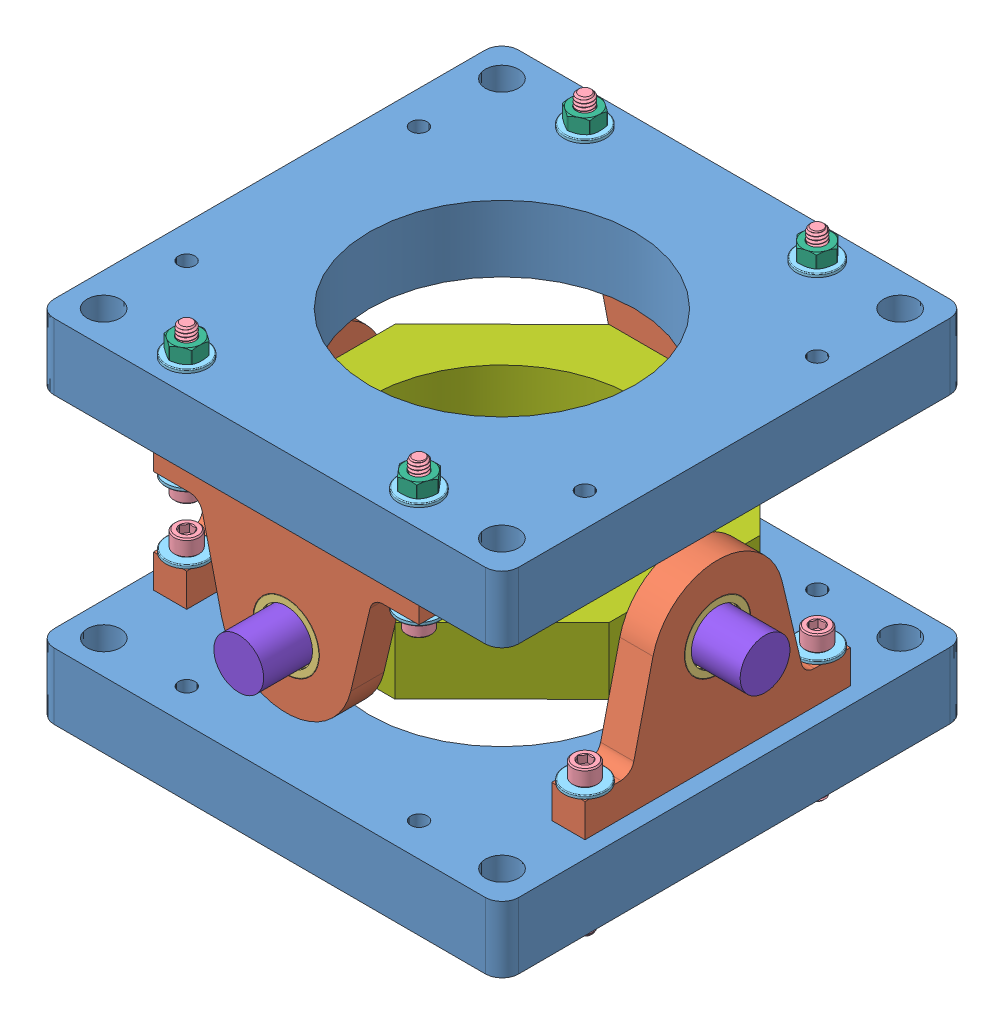
SolidWorks assembly Test Assembly Fixed, configuration Default. Lengths in mm.
Overall size (201.43 158.78 201.4).
62 component instances, 8 part files, 6 mates.
Components (placement in the parent):
- Intermediate Ring with Brackets-1: Intermediate Ring with Brackets [Default] at (212.401 138.376 28.4438) size (177.8 104.64 177.8)
  - Intermediate Ring-2: Intermediate Ring [Default] at (-88.8543 79.5311 225.6413) size (177.8 25.4 177.8)
  - Crosstree Bracket Assembly-1: Crosstree Bracket Assembly [Default] at (-114.4432 107.4664 379.2209) x (1 0 0) z (0 0 -1) size (104.78 104.64 15.88)
    - Crosstree Bracket-1: Crosstree Bracket [Default] at (25.5889 69.8453 71.0296) size (101.6 67.31 12.7)
    - 5905K26_Needle-Roller Bearing-1: 5905K26_Needle-Roller Bearing [5905K26] at (25.5889 69.8453 77.3796) x (-0.328056 0.944658 0) z (0 0 1) size (25.4 25.4 12.7)
    - 90128A253_Zinc-Plated Alloy Steel Socket Head Screw-1: 90128A253_Zinc-Plated Alloy Steel Socket Head Screw [90128A253] at (-18.8611 19.6803 77.3796) x (-0.333308 0 0.942818) z (0 1 0) size (9.53 9.53 57.93)
    - 90107A029_316 Stainless Steel Washer-2: 90107A029_316 Stainless Steel Washer [90107A029] at (-18.8611 41.2703 77.3796) x (1 0 0) z (0 1 0) size (15.88 15.88 1.27)
    - 90128A253_Zinc-Plated Alloy Steel Socket Head Screw-2: 90128A253_Zinc-Plated Alloy Steel Socket Head Screw [90128A253] at (70.0389 19.6803 77.3796) x (1 0 0) z (0 1 0) size (9.53 9.53 57.93)
    - 90107A029_316 Stainless Steel Washer-3: 90107A029_316 Stainless Steel Washer [90107A029] at (70.0389 41.2703 77.3796) x (1 0 0) z (0 1 0) size (15.88 15.88 1.27)
  - Crosstree Bracket Assembly-2: Crosstree Bracket Assembly [Default] at (-114.4432 107.4664 226.8209) x (1 0 0) z (0 0 -1) size (104.78 104.64 15.88)
    - Crosstree Bracket-1: Crosstree Bracket [Default] at (25.5889 69.8453 71.0296) size (101.6 67.31 12.7)
    - 5905K26_Needle-Roller Bearing-1: 5905K26_Needle-Roller Bearing [5905K26] at (25.5889 69.8453 77.3796) x (-0.328056 0.944658 0) z (0 0 1) size (25.4 25.4 12.7)
    - 90128A253_Zinc-Plated Alloy Steel Socket Head Screw-1: 90128A253_Zinc-Plated Alloy Steel Socket Head Screw [90128A253] at (-18.8611 19.6803 77.3796) x (-0.333308 0 0.942818) z (0 1 0) size (9.53 9.53 57.93)
    - 90107A029_316 Stainless Steel Washer-2: 90107A029_316 Stainless Steel Washer [90107A029] at (-18.8611 41.2703 77.3796) x (1 0 0) z (0 1 0) size (15.88 15.88 1.27)
    - 90128A253_Zinc-Plated Alloy Steel Socket Head Screw-2: 90128A253_Zinc-Plated Alloy Steel Socket Head Screw [90128A253] at (70.0389 19.6803 77.3796) x (1 0 0) z (0 1 0) size (9.53 9.53 57.93)
    - 90107A029_316 Stainless Steel Washer-3: 90107A029_316 Stainless Steel Washer [90107A029] at (70.0389 41.2703 77.3796) x (1 0 0) z (0 1 0) size (15.88 15.88 1.27)
  - 1_4_20_Nut Washer Assembly-1: 1_4_20_Nut Washer Assembly [Default] at (-68.2154 77.2758 126.5121) x (0.004746 0 -0.999989) z (0 1 0) size (15.88 15.88 7.21)
    - 90107A029_316 Stainless Steel Washer-1: 90107A029_316 Stainless Steel Washer [90107A029] at (-22.8159 -23.9196 28.2903) size (15.88 15.88 1.27)
    - 95462A029_Medium-Strength Steel Hex Nut-1: 95462A029_Medium-Strength Steel Hex Nut [95462A029] at (-22.8159 -23.9196 31.7034) x (0.972065 0.23471 0) z (0 0 1) size (11.11 12.75 6.32)
  - 1_4_20_Nut Washer Assembly-2: 1_4_20_Nut Washer Assembly [Default] at (-104.6077 77.2758 165.8492) x (0.240016 0 0.970769) z (0 1 0) size (15.88 15.88 7.21)
    - 90107A029_316 Stainless Steel Washer-1: 90107A029_316 Stainless Steel Washer [90107A029] at (-22.8159 -23.9196 28.2903) size (15.88 15.88 1.27)
    - 95462A029_Medium-Strength Steel Hex Nut-1: 95462A029_Medium-Strength Steel Hex Nut [95462A029] at (-22.8159 -23.9196 31.7034) x (0.972065 0.23471 0) z (0 0 1) size (11.11 12.75 6.32)
  - 1_4_20_Nut Washer Assembly-3: 1_4_20_Nut Washer Assembly [Default] at (-104.6027 77.2758 318.2405) x (0.240311 0 0.970696) z (0 1 0) size (15.88 15.88 7.21)
    - 90107A029_316 Stainless Steel Washer-1: 90107A029_316 Stainless Steel Washer [90107A029] at (-22.8159 -23.9196 28.2903) size (15.88 15.88 1.27)
    - 95462A029_Medium-Strength Steel Hex Nut-1: 95462A029_Medium-Strength Steel Hex Nut [95462A029] at (-22.8159 -23.9196 31.7034) x (0.972065 0.23471 0) z (0 0 1) size (11.11 12.75 6.32)
  - 1_4_20_Nut Washer Assembly-4: 1_4_20_Nut Washer Assembly [Default] at (-34.5945 77.2758 270.2742) x (0.895836 0 -0.444384) z (0 1 0) size (15.88 15.88 7.21)
    - 90107A029_316 Stainless Steel Washer-1: 90107A029_316 Stainless Steel Washer [90107A029] at (-22.8159 -23.9196 28.2903) size (15.88 15.88 1.27)
    - 95462A029_Medium-Strength Steel Hex Nut-1: 95462A029_Medium-Strength Steel Hex Nut [95462A029] at (-22.8159 -23.9196 31.7034) x (0.972065 0.23471 0) z (0 0 1) size (11.11 12.75 6.32)
- Intermediate Ring with Brackets-2: Intermediate Ring with Brackets [Default] at (-102.0555 213.6515 343.0246) x (-0.000002 -0.002271 0.999997) z (0.999999 -0.001042 0) size (177.8 104.64 177.8)
  - Intermediate Ring-2: Intermediate Ring [Default] at (-88.8543 79.5311 225.6413) size (177.8 25.4 177.8)
  - Crosstree Bracket Assembly-1: Crosstree Bracket Assembly [Default] at (-114.4432 107.4664 379.2209) x (1 0 0) z (0 0 -1) size (104.78 104.64 15.88)
    - Crosstree Bracket-1: Crosstree Bracket [Default] at (25.5889 69.8453 71.0296) size (101.6 67.31 12.7)
    - 5905K26_Needle-Roller Bearing-1: 5905K26_Needle-Roller Bearing [5905K26] at (25.5889 69.8453 77.3796) x (-0.328056 0.944658 0) z (0 0 1) size (25.4 25.4 12.7)
    - 90128A253_Zinc-Plated Alloy Steel Socket Head Screw-1: 90128A253_Zinc-Plated Alloy Steel Socket Head Screw [90128A253] at (-18.8611 19.6803 77.3796) x (-0.333308 0 0.942818) z (0 1 0) size (9.53 9.53 57.93)
    - 90107A029_316 Stainless Steel Washer-2: 90107A029_316 Stainless Steel Washer [90107A029] at (-18.8611 41.2703 77.3796) x (1 0 0) z (0 1 0) size (15.88 15.88 1.27)
    - 90128A253_Zinc-Plated Alloy Steel Socket Head Screw-2: 90128A253_Zinc-Plated Alloy Steel Socket Head Screw [90128A253] at (70.0389 19.6803 77.3796) x (1 0 0) z (0 1 0) size (9.53 9.53 57.93)
    - 90107A029_316 Stainless Steel Washer-3: 90107A029_316 Stainless Steel Washer [90107A029] at (70.0389 41.2703 77.3796) x (1 0 0) z (0 1 0) size (15.88 15.88 1.27)
  - Crosstree Bracket Assembly-2: Crosstree Bracket Assembly [Default] at (-114.4432 107.4664 226.8209) x (1 0 0) z (0 0 -1) size (104.78 104.64 15.88)
    - Crosstree Bracket-1: Crosstree Bracket [Default] at (25.5889 69.8453 71.0296) size (101.6 67.31 12.7)
    - 5905K26_Needle-Roller Bearing-1: 5905K26_Needle-Roller Bearing [5905K26] at (25.5889 69.8453 77.3796) x (-0.328056 0.944658 0) z (0 0 1) size (25.4 25.4 12.7)
    - 90128A253_Zinc-Plated Alloy Steel Socket Head Screw-1: 90128A253_Zinc-Plated Alloy Steel Socket Head Screw [90128A253] at (-18.8611 19.6803 77.3796) x (-0.333308 0 0.942818) z (0 1 0) size (9.53 9.53 57.93)
    - 90107A029_316 Stainless Steel Washer-2: 90107A029_316 Stainless Steel Washer [90107A029] at (-18.8611 41.2703 77.3796) x (1 0 0) z (0 1 0) size (15.88 15.88 1.27)
    - 90128A253_Zinc-Plated Alloy Steel Socket Head Screw-2: 90128A253_Zinc-Plated Alloy Steel Socket Head Screw [90128A253] at (70.0389 19.6803 77.3796) x (1 0 0) z (0 1 0) size (9.53 9.53 57.93)
    - 90107A029_316 Stainless Steel Washer-3: 90107A029_316 Stainless Steel Washer [90107A029] at (70.0389 41.2703 77.3796) x (1 0 0) z (0 1 0) size (15.88 15.88 1.27)
  - 1_4_20_Nut Washer Assembly-1: 1_4_20_Nut Washer Assembly [Default] at (-68.2154 77.2758 126.5121) x (0.004746 0 -0.999989) z (0 1 0) size (15.88 15.88 7.21)
    - 90107A029_316 Stainless Steel Washer-1: 90107A029_316 Stainless Steel Washer [90107A029] at (-22.8159 -23.9196 28.2903) size (15.88 15.88 1.27)
    - 95462A029_Medium-Strength Steel Hex Nut-1: 95462A029_Medium-Strength Steel Hex Nut [95462A029] at (-22.8159 -23.9196 31.7034) x (0.972065 0.23471 0) z (0 0 1) size (11.11 12.75 6.32)
  - 1_4_20_Nut Washer Assembly-2: 1_4_20_Nut Washer Assembly [Default] at (-104.6077 77.2758 165.8492) x (0.240016 0 0.970769) z (0 1 0) size (15.88 15.88 7.21)
    - 90107A029_316 Stainless Steel Washer-1: 90107A029_316 Stainless Steel Washer [90107A029] at (-22.8159 -23.9196 28.2903) size (15.88 15.88 1.27)
    - 95462A029_Medium-Strength Steel Hex Nut-1: 95462A029_Medium-Strength Steel Hex Nut [95462A029] at (-22.8159 -23.9196 31.7034) x (0.972065 0.23471 0) z (0 0 1) size (11.11 12.75 6.32)
  - 1_4_20_Nut Washer Assembly-3: 1_4_20_Nut Washer Assembly [Default] at (-104.6027 77.2758 318.2405) x (0.240311 0 0.970696) z (0 1 0) size (15.88 15.88 7.21)
    - 90107A029_316 Stainless Steel Washer-1: 90107A029_316 Stainless Steel Washer [90107A029] at (-22.8159 -23.9196 28.2903) size (15.88 15.88 1.27)
    - 95462A029_Medium-Strength Steel Hex Nut-1: 95462A029_Medium-Strength Steel Hex Nut [95462A029] at (-22.8159 -23.9196 31.7034) x (0.972065 0.23471 0) z (0 0 1) size (11.11 12.75 6.32)
  - 1_4_20_Nut Washer Assembly-4: 1_4_20_Nut Washer Assembly [Default] at (-34.5945 77.2758 270.2742) x (0.895836 0 -0.444384) z (0 1 0) size (15.88 15.88 7.21)
    - 90107A029_316 Stainless Steel Washer-1: 90107A029_316 Stainless Steel Washer [90107A029] at (-22.8159 -23.9196 28.2903) size (15.88 15.88 1.27)
    - 95462A029_Medium-Strength Steel Hex Nut-1: 95462A029_Medium-Strength Steel Hex Nut [95462A029] at (-22.8159 -23.9196 31.7034) x (0.972065 0.23471 0) z (0 0 1) size (11.11 12.75 6.32)
- Crosstree Assembly-1: Crosstree Assembly [Default] at (80.4212 101.4137 143.2242) x (0.999999 -0.001042 0) z (0 0 1) size (201.4 26.18 201.4)
  - Crosstree-1: Crosstree [Default] at (43.0477 61.9283 110.8608) size (139.7 25.4 139.7)
  - Crosstree Bearing Rod-1: Crosstree Bearing Rod [Default] at (43.0477 74.6283 10.1618) x (-0.520451 0.853891 0) z (0.853891 0.520451 0) size (19.05 50.8 19.05)
  - Crosstree Bearing Rod-2: Crosstree Bearing Rod [Default] at (143.7467 74.6283 110.8608) x (0 0.853891 -0.520451) z (0 0.520451 0.853891) size (19.05 50.8 19.05)
  - Crosstree Bearing Rod-3: Crosstree Bearing Rod [Default] at (43.0477 74.6283 211.5599) x (0.520451 0.853891 0) z (-0.853891 0.520451 0) size (19.05 50.8 19.05)
  - Crosstree Bearing Rod-4: Crosstree Bearing Rod [Default] at (-57.6514 74.6283 110.8608) x (0 0.853891 0.520451) z (0 0.520451 -0.853891) size (19.05 50.8 19.05)
Mates (geometry in assembly coordinates):
- Concentric2: concentric anti-aligned: cylinder of Intermediate Ring with Brackets-1/Crosstree Bracket Assembly-1/5905K26_Needle-Roller Bearing-1 through (123.5466 175.9971 323.935) axis (0 0 -1) radius 11.6417; cylinder of Crosstree Assembly-1/Crosstree Bearing Rod-3 through (123.5466 175.9971 303.9841) axis (0 0 1) radius 9.525
- Concentric3: concentric aligned: cylinder of Intermediate Ring with Brackets-1/Crosstree Bracket Assembly-2/5905K26_Needle-Roller Bearing-1 through (123.5466 175.9971 171.535) axis (0 0 -1) radius 11.6417; cylinder of Crosstree Assembly-1/Crosstree Bearing Rod-1 through (123.5466 175.9971 204.186) axis (0 0 -1) radius 9.525
- Coincident1: coincident anti-aligned: plane of Intermediate Ring with Brackets-1/Crosstree Bracket Assembly-2/Crosstree Bracket-1 through (123.5466 175.9971 184.235) normal (0 0 1); plane of Crosstree Assembly-1/Crosstree-1 through (152.4927 188.667 184.235) normal (0 0 -1)
- Concentric4: concentric anti-aligned: cylinder of Intermediate Ring with Brackets-2/Crosstree Bracket Assembly-1/5905K26_Needle-Roller Bearing-1 through (193.3966 175.9243 254.085) axis (-0.999999 0.001042 0) radius 11.6417; cylinder of Crosstree Assembly-1/Crosstree Bearing Rod-2 through (173.4457 175.9451 254.085) axis (0.999999 -0.001042 0) radius 9.525
- Concentric5: concentric aligned: cylinder of Intermediate Ring with Brackets-2/Crosstree Bracket Assembly-2/5905K26_Needle-Roller Bearing-1 through (40.9967 176.0831 254.085) axis (-0.999999 0.001042 0) radius 11.6417; cylinder of Crosstree Assembly-1/Crosstree Bearing Rod-4 through (73.6476 176.0491 254.085) axis (-0.999999 0.001042 0) radius 9.525
- Coincident2: coincident anti-aligned: plane of Intermediate Ring with Brackets-2/Crosstree Bracket Assembly-2/Crosstree Bracket-1 through (53.6967 176.0699 254.085) normal (0.999999 -0.001042 0); plane of Crosstree Assembly-1/Crosstree-1 through (53.7099 188.7699 225.1522) normal (-0.999999 0.001042 0)
